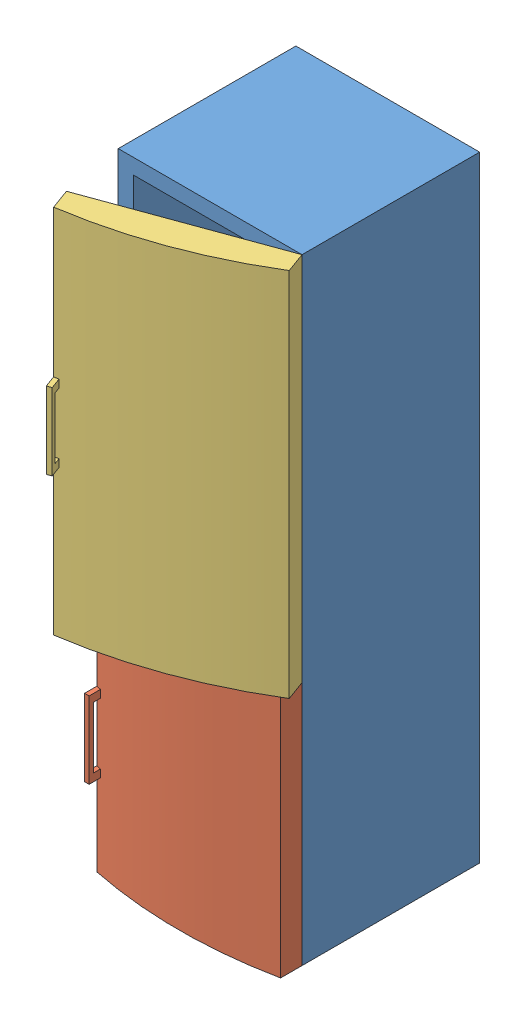
SolidWorks assembly Kühlschrank, configuration Standard. Lengths in mm.
Overall size (637.61 2010 888.53).
3 component instances, 3 part files, 5 mates.
Components (placement in the parent):
- Back-1: Back [Standard] at (-291.9797 -857.3881 2010) size (600 2010 580)
- Door-Down-1: Door-Down [Standard] at (-291.9797 -857.3881 2300) size (600 800 110)
- Door-Up-1: Door-Up [Standard] at (-273.8959 -57.3881 2402.5828) x (0.939721 0 -0.341943) z (0.341943 0 0.939721) size (600 1210 110)
Mates (geometry in assembly coordinates):
- Deckungsgleich2: coincident aligned: plane of Back-1 through (-291.9797 -857.3881 2010) normal (0 -1 0); plane of Door-Down-1 through (-291.9797 -857.3881 900.3062) normal (0 -1 0)
- Deckungsgleich3: coincident aligned: line of Back-1 through (8.0203 1152.6119 2300) axis (0 -1 0); line of Door-Down-1 through (8.0203 -57.3881 2300) axis (0 -1 0)
- Winkel1: planar angle = 0 rad anti-aligned: plane of Back-1 through (-591.9797 1152.6119 2300) normal (0 0 1); plane of Door-Down-1 through (-591.9797 -57.3881 2300) normal (0 0 -1)
- Deckungsgleich4: coincident aligned: plane of Back-1 through (-291.9797 1152.6119 2010) normal (0 1 0); plane of Door-Up-1 through (-752.511 1152.6119 1087.2614) normal (0 1 0)
- Deckungsgleich5: coincident aligned: line of Back-1 through (8.0203 1152.6119 2300) axis (0 -1 0); line of Door-Up-1 through (8.0203 1152.6119 2300) axis (0 -1 0)
